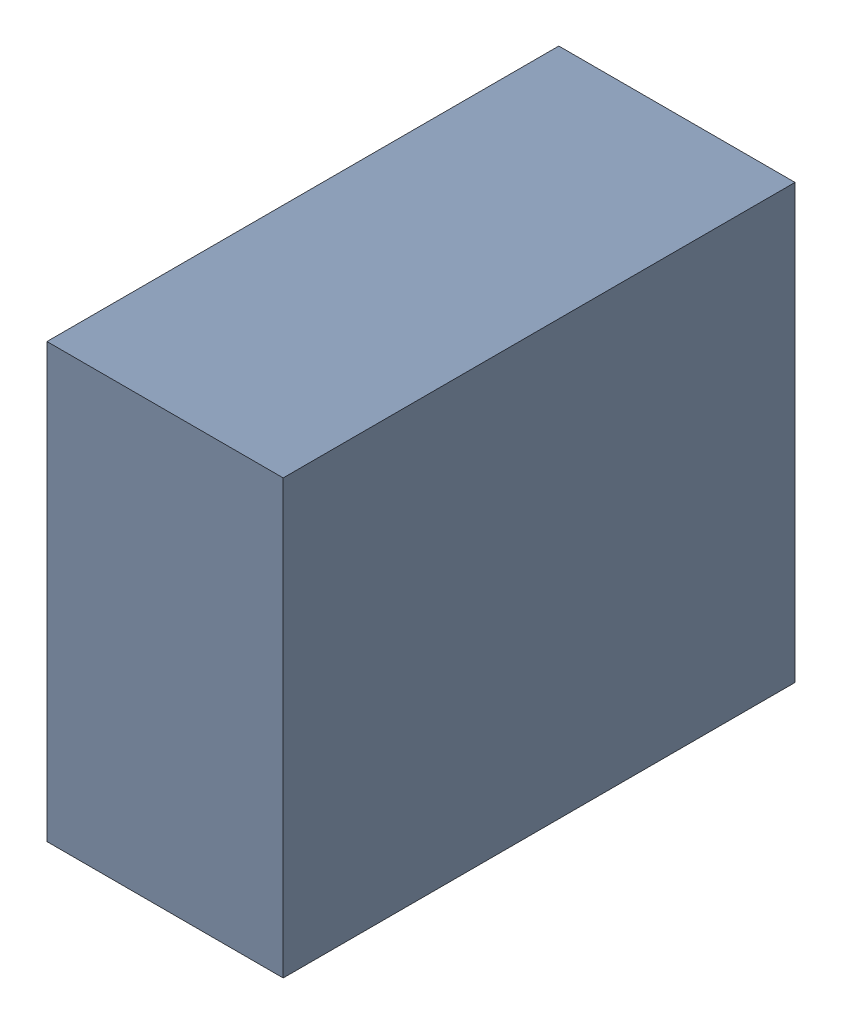
SolidWorks assembly C31_TDA1, configuration Standard. Lengths in mm.
Overall size (0.6 1.1 1.3).
2 component instances, 1 part files, 0 mates.
Components (placement in the parent):
- 885542376-1: 885542376 [Standard] at (-0.95 60.66 0) size (0.6 1.1 1.3)
  - Extruded_25-1: Extruded_25 [Standard] at origin size (0.6 1.1 1.3)
